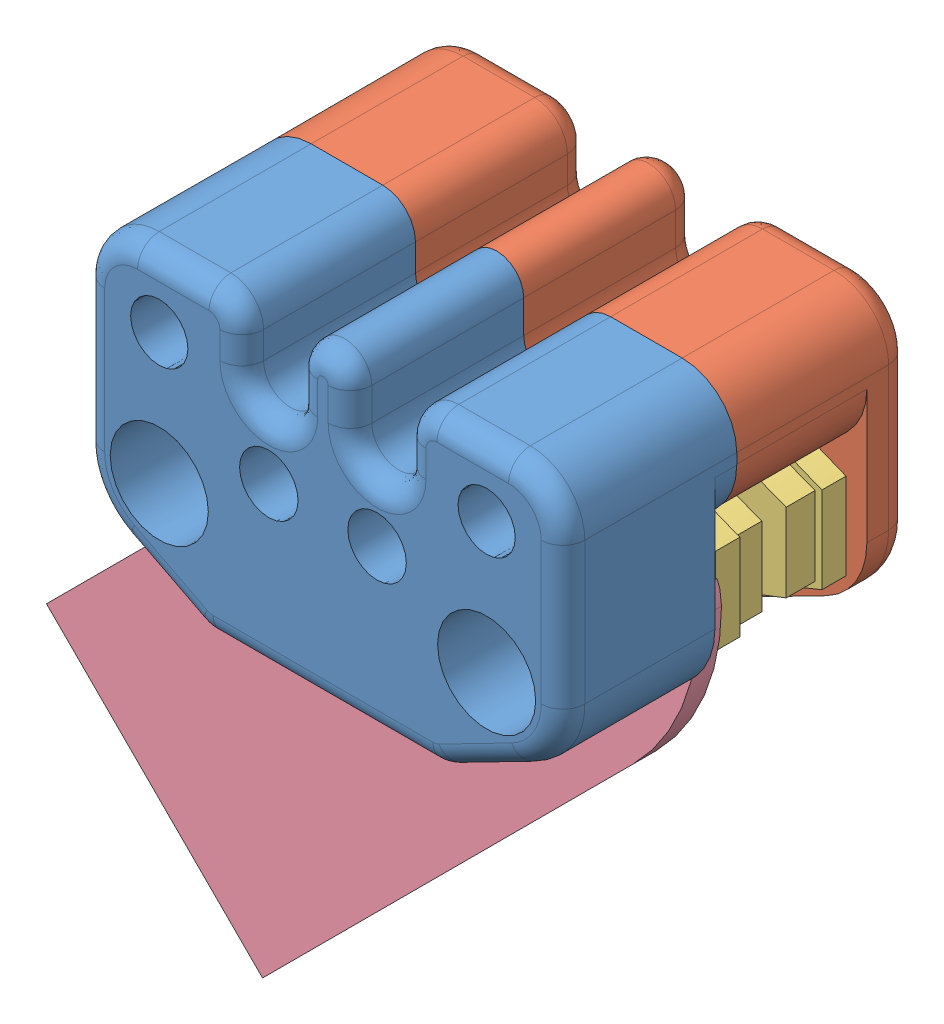
SolidWorks assembly Caliper Assembly, configuration Default. Lengths in mm.
Overall size (113.01 113.01 50.55).
6 component instances, 4 part files, 0 mates.
Components (placement in the parent):
- Caliper Assembly.iam-1: Caliper Assembly.iam [Default] at origin size (113.01 113.01 50.55)
  - Caliper A v2.ipt-1: Caliper A v2.ipt [Default] x (-1 0 0) z (0 0 -1) size (69.85 44.45 25.27)
  - Caliper B v9.ipt-1: Caliper B v9.ipt [Default] at origin size (69.85 44.45 25.27)
  - MCP 554 Pads v5.ipt-1: MCP 554 Pads v5.ipt [Default] at (0.0125 -5.95 -15.4307) x (-1 0 0) z (0 0 -1) size (63.75 26 7.7)
  - MCP 554 Pads v5.ipt-2: MCP 554 Pads v5.ipt [Default] at (-0.0125 -5.95 -3.5) size (63.75 26 7.7)
  - MCP FWB caliper mounting bracket v1.ipt-1: MCP FWB caliper mounting bracket v1.ipt [Default] at (-30.8831 -83.23 3.175) x (-0.707107 0.707107 0) z (0 0 -1) size (58.07 101.75 3.36)
